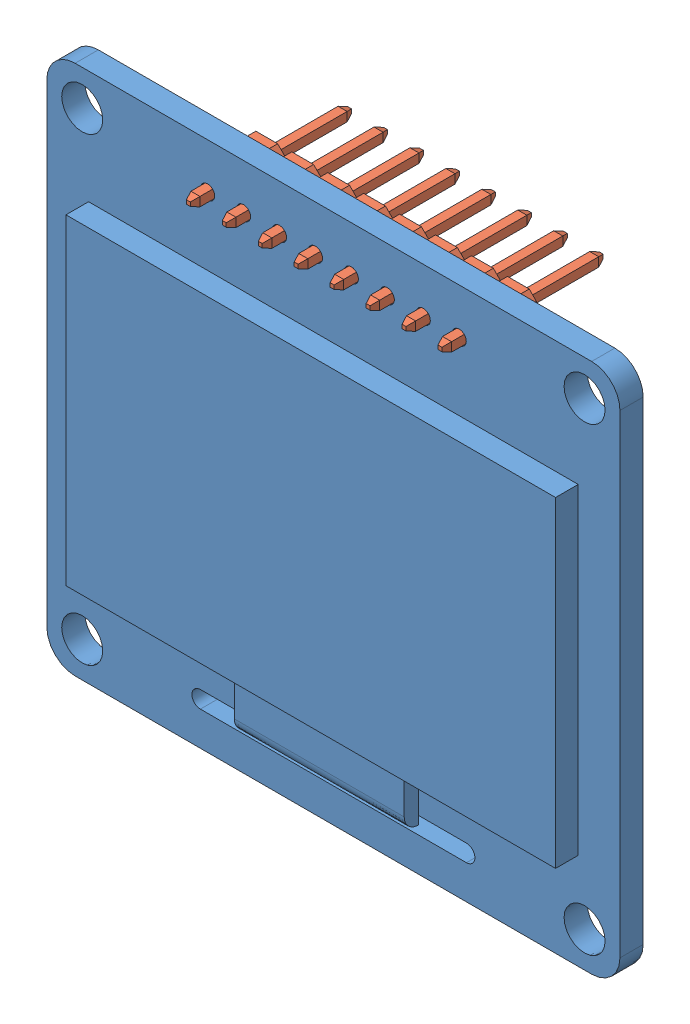
SolidWorks assembly OLED_1.3inch_sh11061b, configuration Default. Lengths in mm.
Overall size (40.5 37.5 11.64).
9 component instances, 2 part files, 0 mates.
Components (placement in the parent):
- OLED_pcb_1.3_1-1: OLED_pcb_1.3_1 [Default] at (-11.6147 51.3978 113.1661) size (40.5 37.5 3.24)
- 2.54mm_pin_header_1-1: 2.54mm_pin_header_1 [Default] at (-2.7247 66.9478 113.1661) x (-1 0 0) z (0 0 -1) size (2.54 2.5 11.4)
- 2.54mm_pin_header_1-2: 2.54mm_pin_header_1 [Default] at (-5.2647 66.9478 113.1661) x (-1 0 0) z (0 0 -1) size (2.54 2.5 11.4)
- 2.54mm_pin_header_1-3: 2.54mm_pin_header_1 [Default] at (-7.8047 66.9478 113.1661) x (-1 0 0) z (0 0 -1) size (2.54 2.5 11.4)
- 2.54mm_pin_header_1-4: 2.54mm_pin_header_1 [Default] at (-10.3447 66.9478 113.1661) x (-1 0 0) z (0 0 -1) size (2.54 2.5 11.4)
- 2.54mm_pin_header_1-5: 2.54mm_pin_header_1 [Default] at (-12.8847 66.9478 113.1661) x (-1 0 0) z (0 0 -1) size (2.54 2.5 11.4)
- 2.54mm_pin_header_1-6: 2.54mm_pin_header_1 [Default] at (-15.4247 66.9478 113.1661) x (-1 0 0) z (0 0 -1) size (2.54 2.5 11.4)
- 2.54mm_pin_header_1-7: 2.54mm_pin_header_1 [Default] at (-17.9647 66.9478 113.1661) x (-1 0 0) z (0 0 -1) size (2.54 2.5 11.4)
- 2.54mm_pin_header_1-8: 2.54mm_pin_header_1 [Default] at (-20.5047 66.9478 113.1661) x (-1 0 0) z (0 0 -1) size (2.54 2.5 11.4)
